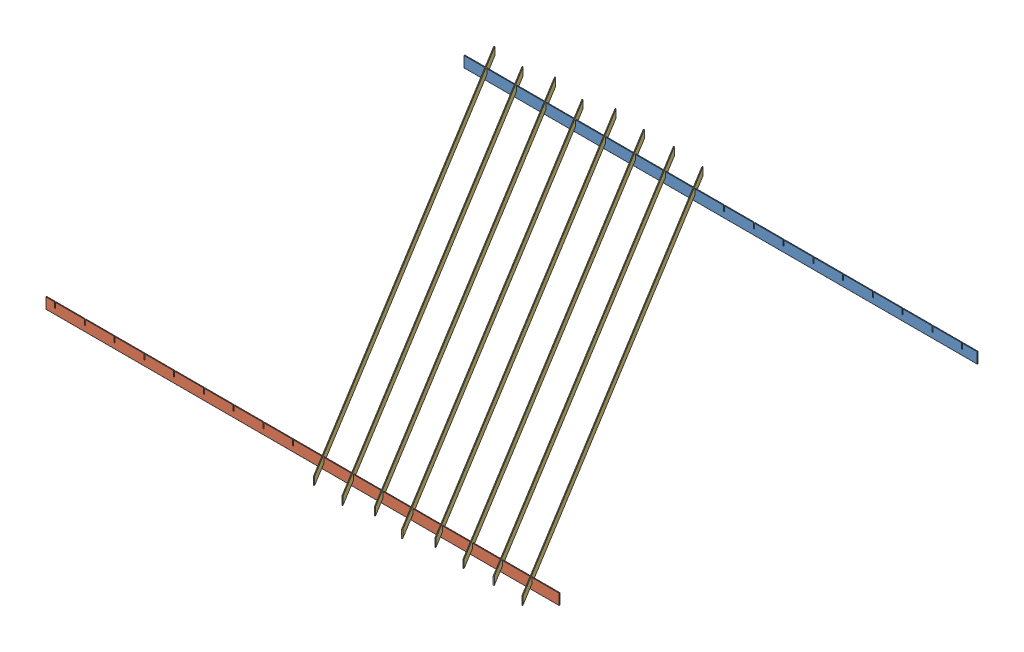
SolidWorks assembly FlatBar_Assembly_tester, configuration Default. Lengths in mm.
Overall size (1896 50 1745.31).
10 component instances, 3 part files, 29 mates.
Components (placement in the parent):
- Flatbar_Holder_2-1: Flatbar_Holder_2 [Default] at (0 0 -1545) x (1 0 0) z (0 -1 0) size (1896 3 40)
- FlatBar_Holder_1-1: FlatBar_Holder_1 [Default] at origin size (1896 40 3)
- FlatBar_Template-1: FlatBar_Template [Default] at (378.8083 15 -764.6195) x (0.853646 0 -0.520854) z (0.520854 0 0.853646) size (3 30 2000)
- FlatBar_Template-2: FlatBar_Template [Default] at (261.5527 15 -776.511) x (0.853646 0 -0.520854) z (0.520854 0 0.853646) size (3 30 2000)
- FlatBar_Template-3: FlatBar_Template [Default] at (151.7922 15 -774.7745) x (0.853646 0 -0.520854) z (0.520854 0 0.853646) size (3 30 2000)
- FlatBar_Template-4: FlatBar_Template [Default] at (32.9462 15 -789.2725) x (0.853646 0 -0.520854) z (-0.520854 0 -0.853646) size (3 30 2000)
- FlatBar_Template-5: FlatBar_Template [Default] at (-179.7397 15 -778.6291) x (0.853646 0 -0.520854) z (0.520854 0 0.853646) size (3 30 2000)
- FlatBar_Template-6: FlatBar_Template [Default] at (-57.4253 15 -757.1027) x (0.853646 0 -0.520854) z (0.520854 0 0.853646) size (3 30 2000)
- FlatBar_Template-7: FlatBar_Template [Default] at (-273.9933 15 -752.8218) x (0.853646 0 -0.520854) z (0.520854 0 0.853646) size (3 30 2000)
- FlatBar_Template-8: FlatBar_Template [Default] at (-389.9962 15 -764.0041) x (0.853646 0 -0.520854) z (0.520854 0 0.853646) size (3 30 2000)
Mates (geometry in assembly coordinates):
- Coincident3: coordinate: point of FlatBar_Holder_1-1
- Parallel2: parallel anti-aligned: plane of Flatbar_Holder_2-1 through (0 0 -1543.5) normal (0 0 1); plane of FlatBar_Holder_1-1 through (0 0 -1.5) normal (0 0 -1)
- Coincident7: coincident aligned: plane of Flatbar_Holder_2-1 through (-948 -20 -1546.5) normal (0 -1 0); plane of FlatBar_Holder_1-1 through (948 -20 -1.5) normal (0 -1 0)
- Coincident6: coincident: plane of Flatbar_Holder_2-1 through (0 0 -1546.5) normal (0 0 -1)
- Coincident10: coincident aligned: plane of Flatbar_Holder_2-1 through (-948 -20 -1546.5) normal (-1 0 0); plane of FlatBar_Holder_1-1 through (-948 -20 -1.5) normal (-1 0 0)
- Coincident11: coincident anti-aligned: plane of FlatBar_Holder_1-1 through (843.49 0 -1.5) normal (0 1 0); plane of FlatBar_Template-1 through (-143.0272 0 -1617.6665) normal (0 -1 0)
- Tangent2: tangent: line of FlatBar_Holder_1-1 through (843.49 19.65 -1.5) axis (0 -1 0); cylinder of FlatBar_Template-1 through (-143.0272 29.65 -1617.6665) axis (0.520854 0 0.853646) radius 0.35
- Tangent3: tangent: line of Flatbar_Holder_2-1 through (-95.49 0 -1543.5) axis (0 1 0); cylinder of FlatBar_Template-1 through (-141.0638 29.65 -1618.8645) axis (0.520854 0 0.853646) radius 0.35
- Coincident15: coincident anti-aligned: plane of Flatbar_Holder_2-1 through (-209.49 0 -1546.5) normal (0 1 0); plane of FlatBar_Template-2 through (-260.2828 0 -1629.558) normal (0 -1 0)
- Tangent4: tangent: line of Flatbar_Holder_2-1 through (-205.49 0 -1543.5) axis (0 1 0); cylinder of FlatBar_Template-2 through (-258.3194 29.65 -1630.756) axis (0.520854 0 0.853646) radius 0.35
- Coincident16: coincident anti-aligned: plane of FlatBar_Holder_1-1 through (623.49 0 -1.5) normal (0 1 0); plane of FlatBar_Template-3 through (-370.0432 0 -1627.8215) normal (0 -1 0)
- Tangent7: tangent: line of Flatbar_Holder_2-1 through (-315.49 0 -1543.5) axis (0 1 0); cylinder of FlatBar_Template-3 through (-368.0799 29.65 -1629.0194) axis (0.520854 0 0.853646) radius 0.35
- Parallel11: parallel aligned: plane of FlatBar_Template-2 through (-260.5815 0.35 -1629.3757) normal (-0.853646 0 0.520854); plane of FlatBar_Template-3 through (-370.342 0.35 -1627.6392) normal (-0.853646 0 0.520854)
- Parallel12: parallel aligned: plane of FlatBar_Template-1 through (-143.3259 0.35 -1617.4842) normal (-0.853646 0 0.520854); plane of FlatBar_Template-2 through (-260.5815 0.35 -1629.3757) normal (-0.853646 0 0.520854)
- Parallel13: parallel aligned: plane of FlatBar_Template-3 through (-370.342 0.35 -1627.6392) normal (-0.853646 0 0.520854); plane of FlatBar_Template-4 through (552.5195 29.65 65.1547) normal (-0.853646 0 0.520854)
- Tangent8: tangent: line of Flatbar_Holder_2-1 through (-425.49 0 -1543.5) axis (0 1 0); cylinder of FlatBar_Template-4 through (554.7817 0.35 63.7745) axis (-0.520854 0 -0.853646) radius 0.35
- Coincident26: coincident anti-aligned: plane of Flatbar_Holder_2-1 through (-429.49 0 -1546.5) normal (0 1 0); plane of FlatBar_Template-4 through (552.8183 0 64.9724) normal (0 -1 0)
- Parallel14: parallel anti-aligned: plane of FlatBar_Template-4 through (552.5195 29.65 65.1547) normal (-0.853646 0 0.520854); plane of FlatBar_Template-6 through (-576.9986 0.35 -1611.53) normal (0.853646 0 -0.520854)
- Parallel15: parallel anti-aligned: plane of FlatBar_Template-4 through (552.5195 29.65 65.1547) normal (-0.853646 0 0.520854); plane of FlatBar_Template-5 through (-699.3129 0.35 -1633.0563) normal (0.853646 0 -0.520854)
- Parallel16: parallel anti-aligned: plane of FlatBar_Template-4 through (552.5195 29.65 65.1547) normal (-0.853646 0 0.520854); plane of FlatBar_Template-7 through (-793.5666 0.35 -1607.2491) normal (0.853646 0 -0.520854)
- Parallel17: parallel anti-aligned: plane of FlatBar_Template-4 through (552.5195 29.65 65.1547) normal (-0.853646 0 0.520854); plane of FlatBar_Template-8 through (-909.5694 0.35 -1618.4313) normal (0.853646 0 -0.520854)
- Tangent9: tangent: line of Flatbar_Holder_2-1 through (-535.49 0 -1543.5) axis (0 1 0); cylinder of FlatBar_Template-6 through (-577.2974 29.65 -1611.3477) axis (0.520854 0 0.853646) radius 0.35
- Coincident32: coincident anti-aligned: plane of Flatbar_Holder_2-1 through (-539.49 0 -1546.5) normal (0 1 0); plane of FlatBar_Template-6 through (-579.2608 0 -1610.1497) normal (0 -1 0)
- Coincident33: coincident anti-aligned: plane of FlatBar_Holder_1-1 through (293.49 0 -1.5) normal (0 1 0); plane of FlatBar_Template-5 through (-701.5751 0 -1631.676) normal (0 -1 0)
- Tangent10: tangent: line of FlatBar_Holder_1-1 through (293.49 19.65 -1.5) axis (0 -1 0); cylinder of FlatBar_Template-5 through (-701.5751 29.65 -1631.676) axis (0.520854 0 0.853646) radius 0.35
- Coincident35: coincident anti-aligned: plane of FlatBar_Holder_1-1 through (183.49 0 -1.5) normal (0 1 0); plane of FlatBar_Template-7 through (-795.8288 0 -1605.8688) normal (0 -1 0)
- Tangent11: tangent: line of FlatBar_Holder_1-1 through (183.49 19.65 -1.5) axis (0 -1 0); cylinder of FlatBar_Template-7 through (-795.8288 29.65 -1605.8688) axis (0.520854 0 0.853646) radius 0.35
- Coincident37: coincident anti-aligned: plane of FlatBar_Holder_1-1 through (73.49 0 -1.5) normal (0 1 0); plane of FlatBar_Template-8 through (-911.8316 0 -1617.051) normal (0 -1 0)
- Tangent12: tangent: line of FlatBar_Holder_1-1 through (73.49 19.65 -1.5) axis (0 -1 0); cylinder of FlatBar_Template-8 through (-911.8316 29.65 -1617.051) axis (0.520854 0 0.853646) radius 0.35
